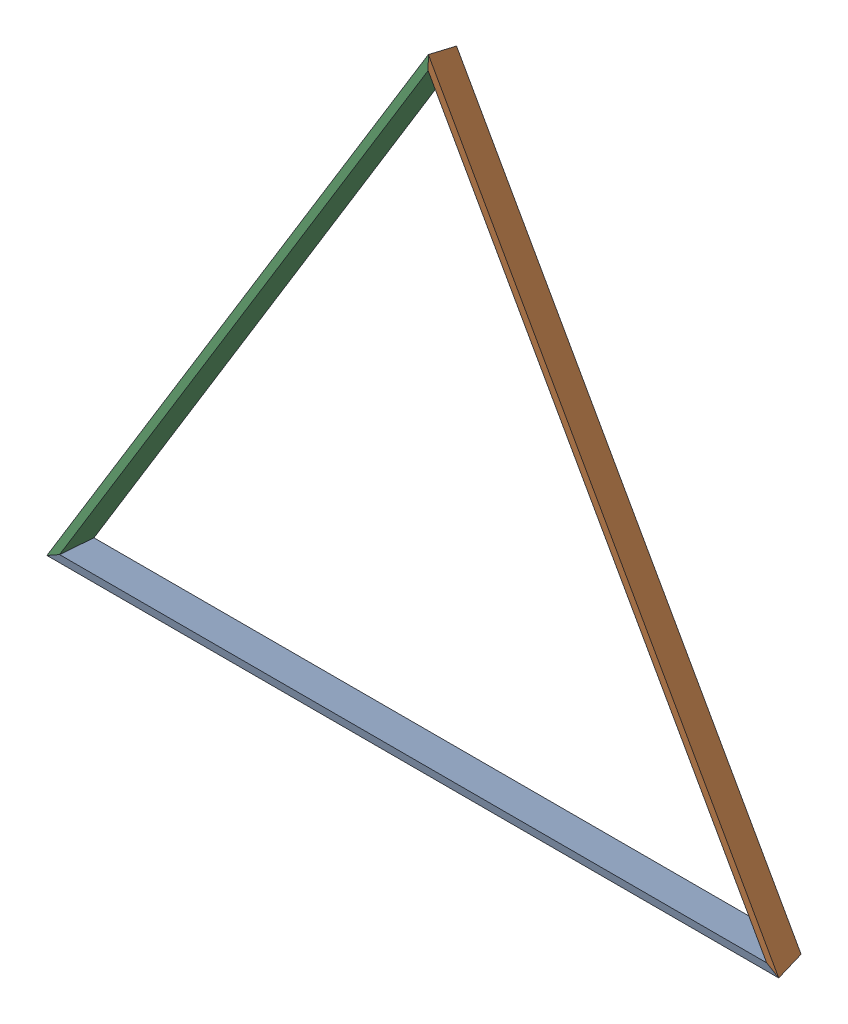
SolidWorks assembly hex_1_1, configuration Default. Lengths in mm.
Overall size (3132.81 3334.25 2398.03).
3 component instances, 3 part files, 0 mates.
Components (placement in the parent):
- dome-hex_A_1-1: dome-hex_A_1 [Default] at (-54.8338 723.4273 -6076.5179) x (-0.072057 -0.575985 0.814278) z (-0.865209 0.442256 0.236269) size (283.93 1314.1 2231.51)
- dome-hex_B_1-1: dome-hex_B_1 [Default] at (-54.8338 723.4273 -6076.5179) x (-0.072057 -0.575985 0.814278) z (-0.865209 0.442256 0.236269) size (1246.15 959.88 2041.73)
- dome-hex_C_1-1: dome-hex_C_1 [Default] at (-54.8338 723.4273 -6076.5179) x (-0.072057 -0.575985 0.814278) z (-0.865209 0.442256 0.236269) size (1432 2214.62 244.45)
